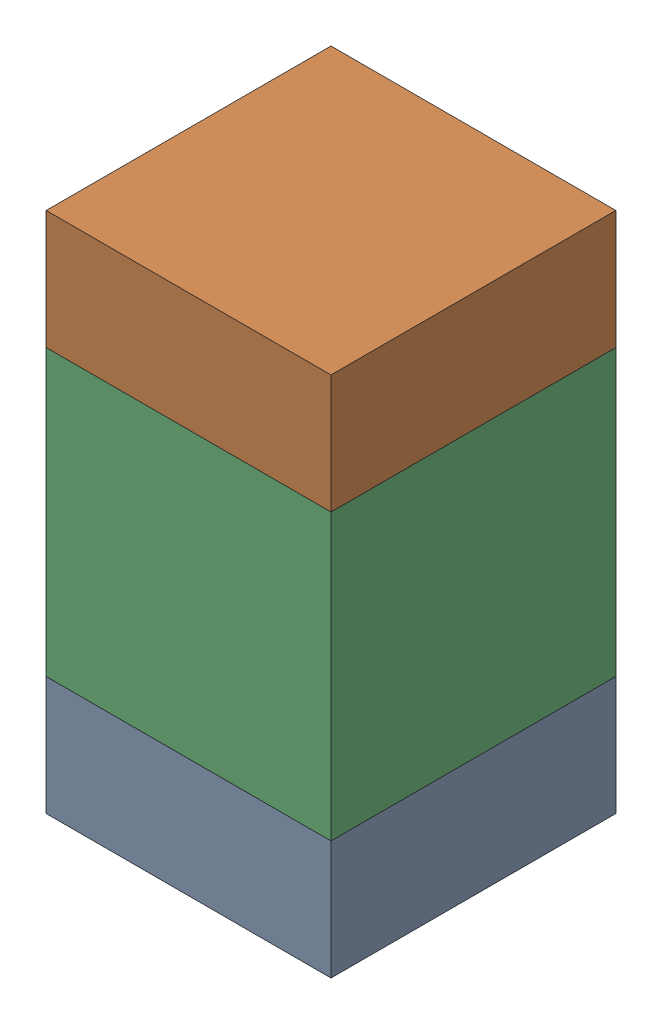
SolidWorks assembly C312_2PCB, configuration Default. Lengths in mm.
Overall size (0.6 1.1 0.6).
6 component instances, 2 part files, 0 mates.
Components (placement in the parent):
- 854785296-1: 854785296 [Default] at (127.3 94.375 0) size (0.6 0.25 0.6)
  - Extruded_10-1: Extruded_10 [Default] at origin size (0.6 0.25 0.6)
- 854785296-2: 854785296 [Default] at (127.3 95.225 0) size (0.6 0.25 0.6)
  - Extruded_10-1: Extruded_10 [Default] at origin size (0.6 0.25 0.6)
- 761606048-1: 761606048 [Default] at (127.3 94.8 0) size (0.6 0.6 0.6)
  - Extruded_9-1: Extruded_9 [Default] at origin size (0.6 0.6 0.6)
